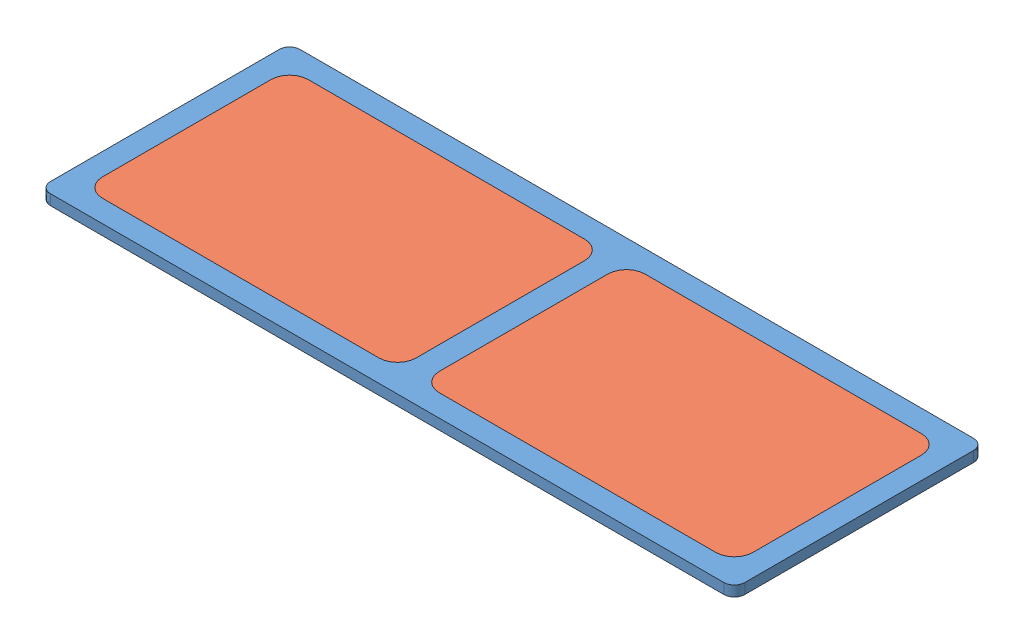
SolidWorks assembly top_lid_assembly, configuration Default. Lengths in mm.
Overall size (538.7 9 215.4).
3 component instances, 2 part files, 4 mates.
Components (placement in the parent):
- lid_rectangular-1: lid_rectangular [Default] at (25.7039 60.1265 -261.3321) x (1 0 0) z (0 -1 0) size (538.7 215.4 9)
- Lid_window-5: Lid_window [Default] at (-254.7961 60.1265 -261.3321) x (1 0 0) z (0 -1 0) size (225.62 177.4 6)
- Lid_window-7: Lid_window [Default] at (35.7039 54.1265 -63.9321) x (1 0 0) z (0 1 0) size (225.62 177.4 6)
Mates (geometry in assembly coordinates):
- Coincident5: coincident anti-aligned: plane of lid_rectangular-1 through (-208.6461 54.1265 -235.3321) normal (0 1 0); plane of Lid_window-5 through (-20.4461 54.1265 -235.3321) normal (0 -1 0)
- Concentric1: concentric: cylinder of lid_rectangular-1 through (-208.6461 54.1265 -89.9321) axis (0 1 0) radius 16; cylinder of Lid_window-5 through (-238.7961 54.1265 -89.9321) axis (0 1 0) radius 16
- Coincident6: coincident: plane of lid_rectangular-1 through (290.2039 54.1265 -235.3321) normal (0 1 0); plane of Lid_window-7 through (290.2039 54.1265 -89.9321) normal (0 -1 0)
- Concentric2: concentric: cylinder of lid_rectangular-1 through (290.2039 54.1265 -235.3321) axis (0 1 0) radius 16; cylinder of Lid_window-7 through (290.2039 60.1265 -235.3321) axis (0 -1 0) radius 16
